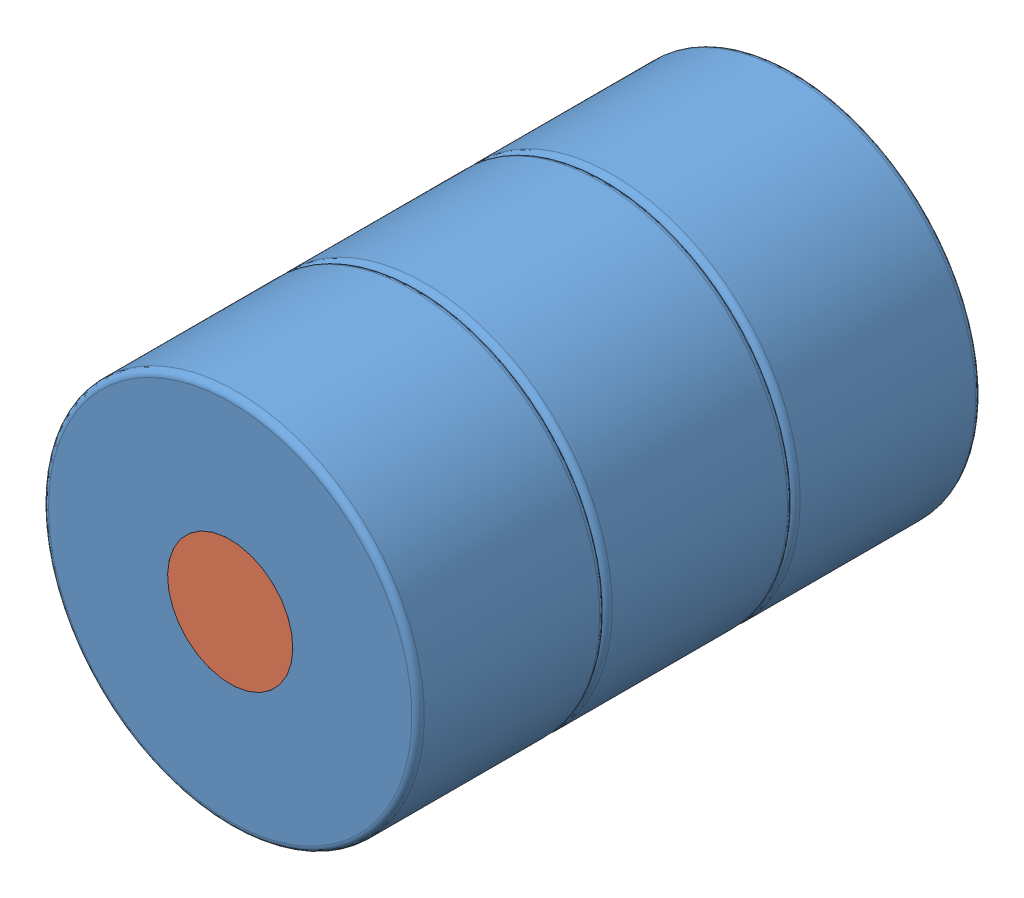
SolidWorks assembly 3bearing, configuration Default. Lengths in mm.
Overall size (6.15 6.15 9).
4 component instances, 2 part files, 3 mates.
Components (placement in the parent):
- ballbearing-1: ballbearing [Default] at (-29.77 32.7716 38.3876) x (0 0 1) z (-0.999686 0.025064 0) size (3 6 6)
- ballbearing-2: ballbearing [Default] at (-29.77 32.7716 32.3876) x (0 0 1) z (-0.999686 0.025064 0) size (3 6 6)
- ballbearing-3: ballbearing [Default] at (-29.77 32.7716 35.3876) x (0 0 1) z (-0.999686 0.025064 0) size (3 6 6)
- Copy of Part3^3bearing-1: Copy of Part3^3bearing [Default] at (-50.4485 1.0576 32.3876) size (2 2 9) (virtual)
Mates (geometry in assembly coordinates):
- Coincident8: coincident aligned: plane of ballbearing-1 through (-29.77 32.7716 41.3876) normal (0 0 1); plane of Copy of Part3^Assem1_Finger-1 through (-29.77 32.7716 41.3876) normal (0 0 1)
- Concentric3: concentric aligned: cylinder of ballbearing-1 through (-29.77 32.7716 41.3876) axis (0 0 -1) radius 1; cylinder of Copy of Part3^Assem1_Finger-1 through (-29.77 32.7716 41.3876) axis (0 0 -1) radius 1
- Concentric5: concentric aligned: cylinder of ballbearing-3 through (-29.77 32.7716 38.3876) axis (0 0 -1) radius 1; cylinder of Copy of Part3^Assem1_Finger-1 through (-29.77 32.7716 41.3876) axis (0 0 -1) radius 1
